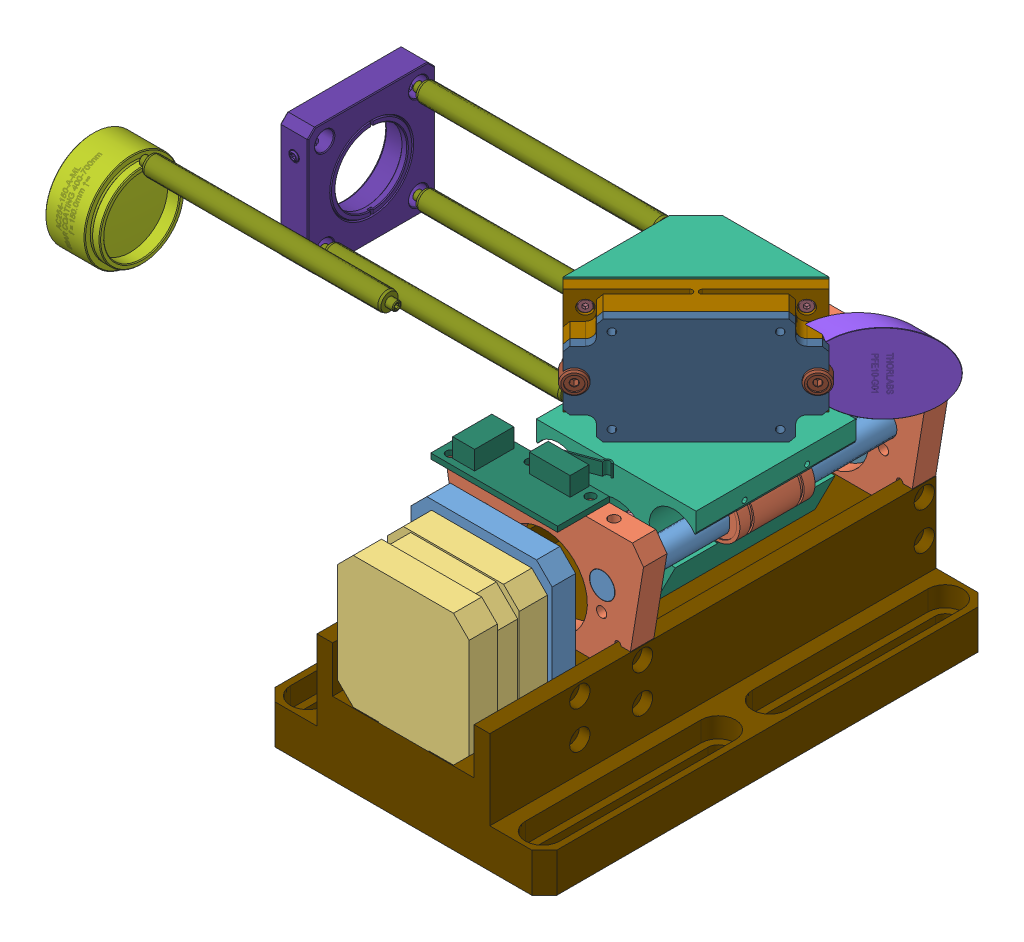
SolidWorks assembly Linear Stage, configuration Default. Lengths in mm.
Overall size (175.66 121.54 148).
36 component instances, 22 part files, 72 mates.
Components (placement in the parent):
- BI004-A - Linear Axis 8mm-3: BI004-A - Linear Axis 8mm [Default] at (44.95 27.15 -20.5) x (0 0 -1) z (-0.759211 0.650845 0) size (97.5 8 8)
- LM8UU - LinearBearing8mm-1: LM8UU - LinearBearing8mm [Default] at (44.95 28.65 -68.9607) x (0 0 -1) z (0.208321 -0.978061 0) size (24 15 15)
- BI004-A - Linear Axis 8mm-2: BI004-A - Linear Axis 8mm [Default] at (81.95 27.15 -20.5) x (0 0 -1) z (0.802037 -0.597275 0) size (97.5 8 8)
- LM8UU - LinearBearing8mm-2: LM8UU - LinearBearing8mm [Default] at (81.95 28.65 -68.9607) x (0 0 -1) z (0.231278 0.972888 0) size (24 15 15)
- BI002-A - NEMA17-L27-1: BI002-A - NEMA17-L27 [Default] at (63.45 19.65 12) x (0 0 1) z (-1 0 0) size (51 48 42)
- TR8x2 - TrapeziumStud8mm-1: TR8x2 - TrapeziumStud8mm [Default] at (63.45 19.65 -37.5) x (0 0 -1) z (-0.999958 0.009122 0) size (87.25 8 9.24)
- TR8x2 - LeadScrew8mm-1: TR8x2 - LeadScrew8mm [Default] at (63.45 19.65 -92.9607) x (0 0 -1) z (0.707107 -0.707107 0) size (15.5 22 22)
- BI005-A - AxisAdapterInt5mmInt8mm-1: BI005-A - AxisAdapterInt5mmInt8mm [Default] at (63.45 19.65 -19.5) x (0 0 -1) z (0.820702 -0.571356 0) (suppressed, hidden)
- CR050-A - Mounting-1: CR050-A - Mounting [Default] at (63.45 39.65 -43.4607) x (-1 0 0) z (0 0 -1) size (51 66.5 51)
- AC254-150-A-ML-1: AC254-150-A-ML [Default] at (-56.1614 71.7257 -4.5809) x (-1 0 0) z (0 0.913882 -0.405979) size (15.71 30.48 30.48)
- PFE10-G01 - EllipticalMirrorSM1-1: PFE10-G01 - EllipticalMirrorSM1 [Default] at (94.0995 57.15 -93.9534) x (0 1 0) z (-1 0 -0.000029) size (25.4 25.4 33.53)
- CR049-A - MirrorRotMount-1: CR049-A - MirrorRotMount [Default] at (63.45 57.15 -68.9607) x (-0.707107 0 0.707107) z (-0.707107 0 -0.707107) size (60 34 12.75)
- CR047-A - BackPlateMirror-1: CR047-A - BackPlateMirror [Default] at (68.223 57.15 -64.1878) x (0.707107 0 -0.707107) z (0.707107 0 0.707107) size (60 34 3)
- MAS15-1: MAS15 [Default] at (79.8758 56.2761 -93.0822) x (0.592527 -0.545732 -0.592527) z (-0.707107 0 -0.707107) size (7.11 7.11 23.88)
- MAS15-2: MAS15 [Default] at (39.3448 58.0539 -52.5512) x (-0.582343 0.567233 0.582343) z (-0.707107 0 -0.707107) size (7.11 7.11 23.88)
- CR048-A - HoldPlate-3: CR048-A - HoldPlate [Default] at (64.1571 57.15 -68.2536) x (-0.707107 0 0.707107) z (0 -1 0) size (50.25 1 25.75)
- socket head cap screw_din-2: socket head cap screw_din [DIN 912 M2 x 3 --- 3N] at (44.0753 69.15 -52.9801) x (-0.707107 0 -0.707107) z (0.707107 0 -0.707107) size (5 3.8 3.8)
- socket head cap screw_din-3: socket head cap screw_din [DIN 912 M2 x 3 --- 3N] at (44.0753 45.15 -52.9801) x (-0.707107 0 -0.707107) z (0.707107 0 -0.707107) size (5 3.8 3.8)
- socket head cap screw_din-4: socket head cap screw_din [DIN 912 M2 x 3 --- 3N] at (79.4306 69.15 -88.3355) x (-0.707107 0 -0.707107) z (0.707107 0 -0.707107) size (5 3.8 3.8)
- socket head cap screw_din-5: socket head cap screw_din [DIN 912 M2 x 3 --- 3N] at (79.4306 45.15 -88.3355) x (-0.707107 0 -0.707107) z (0.707107 0 -0.707107) size (5 3.8 3.8)
- KFL8 - RotationBearing8mm-1: KFL8 - RotationBearing8mm [Default] at (63.45 19.65 -122.5) x (-1 0 0) z (0 1 0) size (47.5 11 26.5)
- BI005-A - SwitchSensor-1: BI005-A - SwitchSensor [Default] at (36.1991 43.65 -11.5) size (40.5 7.7 21.9)
- ER3-5: ER3 [Default] at (2.3359 42.613 -52.5039) x (0 0.898414 0.439149) z (0 -0.439149 0.898414) size (5.99 81.28 5.99)
- CP02_M-1: CP02_M [Default] at (-44.5855 57.15 -68.9607) x (0 0 -1) z (1 0 0) size (41.4 40.64 8.89)
- ER3-7: ER3 [Default] at (-0.4744 93.1408 2.1008) x (0 0.898414 0.439149) z (0 -0.439149 0.898414) size (5.99 81.28 5.99)
- ER3-6: ER3 [Default] at (2.3359 70.7018 -84.5388) x (0 -0.90168 0.432405) z (0 -0.432405 -0.90168) size (5.99 81.28 5.99)
- ER3-4: ER3 [Default] at (2.3359 42.5932 -82.4978) x (0 0.892461 0.451125) z (0 -0.451125 0.892461) size (5.99 81.28 5.99)
- CR044-A - BasePlateStage-1: CR044-A - BasePlateStage [Default] at (63.45 -24.85 -46.75) x (0 0 -1) z (1 0 0) size (142.5 38 90)
- CR046-A - StepConnectPlate-1: CR046-A - StepConnectPlate [Default] at (63.45 21.15 -8) x (1 0 0) z (0 -1 0) size (45 7.5 50)
- CR045-A - MountingPlate-3: CR045-A - MountingPlate [Default] at (63.45 -1.35 -28) x (1 0 0) z (0 -1 0) size (63.48 7.5 50)
- CR045-A - MountingPlate-2: CR045-A - MountingPlate [Default] at (63.45 -1.35 -118) x (1 0 0) z (0 -1 0) size (63.48 7.5 50)
- socket head cap screw_din-8: socket head cap screw_din [DIN 912 M3 x 8 --- 8N] at (69.1069 25.3069 -95.9607) x (0 0 1) z (-1 0 0) size (11 5.5 5.5)
- socket head cap screw_din-9: socket head cap screw_din [DIN 912 M3 x 8 --- 8N] at (57.7931 25.3069 -95.9607) x (0 0 1) z (-1 0 0) size (11 5.5 5.5)
- socket head cap screw_din-10: socket head cap screw_din [DIN 912 M3 x 8 --- 8N] at (57.7931 13.9931 -95.9607) x (0 0 1) z (-1 0 0) size (11 5.5 5.5)
- socket head cap screw_din-11: socket head cap screw_din [DIN 912 M3 x 8 --- 8N] at (69.1069 13.9931 -95.9607) x (0 0 1) z (-1 0 0) size (11 5.5 5.5)
- TR8x2 - FollowScrew8mm-1: TR8x2 - FollowScrew8mm [Default] at (63.45 19.65 -61.9607) x (0 0 1) z (-0.742227 -0.670149 0) size (15.5 14 14)
Mates (geometry in assembly coordinates):
- Coincident2: coincident: plane of BI002-A - NEMA17-L27-1 through (63.45 19.65 24.5) normal (0 0 1); plane of CR044-A - BasePlateStage-1 through (63.45 -12.35 24.5) normal (0 0 1)
- Concentric1: concentric: cylinder of BI002-A - NEMA17-L27-1 through (63.45 19.65 -26.5) axis (0 0 1) radius 2.5; cylinder of BI005-A - AxisAdapterInt5mmInt8mm-1 through (63.45 19.65 -26.5) axis (0 0 1) radius 2.5
- Coincident3: coincident: plane of BI002-A - NEMA17-L27-1 through (63.45 19.65 -26.5) normal (0 0 -1); plane of BI005-A - AxisAdapterInt5mmInt8mm-1 through (63.45 19.65 -26.5) normal (0 0 -1)
- Coincident4: coincident: plane of BI002-A - NEMA17-L27-1 through (63.45 19.65 -0.5) normal (0 0 -1); plane of CR046-A - StepConnectPlate-1 through (63.45 21.15 -0.5) normal (0 0 1)
- Concentric4: concentric: cylinder of BI002-A - NEMA17-L27-1 through (78.95 35.15 -0.5) axis (0 0 -1) radius 1.25; cylinder of CR046-A - StepConnectPlate-1 through (78.95 35.15 -8) axis (0 0 -1) radius 1.6
- Concentric5: concentric: cylinder of BI002-A - NEMA17-L27-1 through (47.95 4.15 -0.5) axis (0 0 -1) radius 1.25; cylinder of CR046-A - StepConnectPlate-1 through (47.95 4.15 -8) axis (0 0 -1) radius 1.6
- Concentric6: concentric: cylinder of TR8x2 - TrapeziumStud8mm-1 through (63.45 19.65 -42.5) axis (0 0 1) radius 1; cylinder of BI005-A - AxisAdapterInt5mmInt8mm-1 through (63.45 19.65 -26.5) axis (0 0 -1) radius 4
- Distance7: distance = 7 mm: plane of TR8x2 - TrapeziumStud8mm-1 through (63.45 19.65 -37.5) normal (0 0 1); plane of BI005-A - AxisAdapterInt5mmInt8mm-1 through (63.45 19.65 -44.5) normal (0 0 -1)
- Concentric7: concentric: cylinder of BI005-A - AxisAdapterInt5mmInt8mm-1 through (63.45 19.65 -44.5) axis (0 0 1) radius 9.5; cylinder of CR050-A - Mounting-1 through (63.45 19.65 -43.4597) axis (0 0 -1) radius 5.5
- Parallel1: parallel: plane of CR050-A - Mounting-1 through (88.95 39.65 -94.4607) normal (0 1 0); plane of CR044-A - BasePlateStage-1 through (63.45 13.15 -46.75) normal (0 1 0)
- Distance8: distance = 82 mm: cylinder of CR050-A - Mounting-1 through (88.951 57.15 -68.9607) axis (-1 0 0) radius 12.8397; plane of CR044-A - BasePlateStage-1 through (63.45 -24.85 -46.75) normal (0 -1 0)
- Width13: width: plane of BI002-A - NEMA17-L27-1 through (84.45 35.65 24.5) normal (1 0 0); plane of BI002-A - NEMA17-L27-1 through (42.45 3.65 24.5) normal (-1 0 0); plane of CR044-A - BasePlateStage-1 through (40.85 5.15 24.5) normal (1 0 0); plane of CR044-A - BasePlateStage-1 through (86.05 5.15 24.5) normal (-1 0 0)
- Width14: width: plane of CR045-A - MountingPlate-3 through (40.95 13.25 -20.5) normal (-1 0 0); plane of CR045-A - MountingPlate-3 through (85.95 -1.35 -20.5) normal (1 0 0); plane of CR044-A - BasePlateStage-1 through (40.85 5.15 24.5) normal (1 0 0); plane of CR044-A - BasePlateStage-1 through (86.05 5.15 24.5) normal (-1 0 0)
- Width16: width: plane of CR045-A - MountingPlate-2 through (85.95 -1.35 -110.5) normal (1 0 0); plane of CR045-A - MountingPlate-2 through (40.95 13.25 -110.5) normal (-1 0 0); plane of CR044-A - BasePlateStage-1 through (86.05 5.15 24.5) normal (-1 0 0); plane of CR044-A - BasePlateStage-1 through (40.85 5.15 24.5) normal (1 0 0)
- Coincident9: coincident: plane of CR044-A - BasePlateStage-1 through (63.45 -12.35 -118) normal (0 0 -1); plane of CR045-A - MountingPlate-2 through (63.45 -1.35 -118) normal (0 0 -1)
- Concentric8: concentric: cylinder of KFL8 - RotationBearing8mm-1 through (63.45 19.65 -118) axis (0 0 -1) radius 13.25; cylinder of CR045-A - MountingPlate-2 through (63.45 19.65 -118.001) axis (0 0 1) radius 13.75
- Coincident11: coincident: plane of KFL8 - RotationBearing8mm-1 through (63.45 19.65 -118) normal (0 0 1); plane of CR045-A - MountingPlate-2 through (63.45 -1.35 -118) normal (0 0 -1)
- Concentric9: concentric: cylinder of KFL8 - RotationBearing8mm-1 through (81.75 19.65 -118) axis (0 0 -1) radius 2.65; cylinder of CR045-A - MountingPlate-2 through (81.75 19.65 -118) axis (0 0 -1) radius 1.65
- Width17: width: plane of CR044-A - BasePlateStage-1 through (86.05 -6.35 -28.1) normal (0 0 1); plane of CR044-A - BasePlateStage-1 through (86.05 -6.35 -20.4) normal (0 0 -1); plane of CR045-A - MountingPlate-3 through (63.45 -1.35 -20.5) normal (0 0 1); plane of CR045-A - MountingPlate-3 through (63.45 -1.35 -28) normal (0 0 -1)
- Concentric10: concentric: cylinder of BI004-A - Linear Axis 8mm-2 through (81.95 27.15 -118) axis (0 0 1) radius 4; cylinder of CR045-A - MountingPlate-3 through (81.95 27.15 -20.499) axis (0 0 -1) radius 4.1
- Concentric11: concentric: cylinder of BI004-A - Linear Axis 8mm-3 through (44.95 27.15 -118) axis (0 0 1) radius 4; cylinder of CR045-A - MountingPlate-3 through (44.95 27.15 -20.499) axis (0 0 -1) radius 4.1
- Concentric12: concentric: cylinder of LM8UU - LinearBearing8mm-2 through (81.95 28.65 -58.2941) axis (0 0 1) radius 7.5; cylinder of CR050-A - Mounting-1 through (81.95 28.65 -43.4597) axis (0 0 -1) radius 7.75
- Width18: width: plane of CR050-A - Mounting-1 through (63.45 39.65 -94.4607) normal (0 0 -1); plane of CR050-A - Mounting-1 through (63.45 39.65 -43.4607) normal (0 0 1); plane of LM8UU - LinearBearing8mm-2 through (80.4467 22.3262 -57.2107) normal (0 0 1); plane of LM8UU - LinearBearing8mm-2 through (81.0249 24.7584 -80.7107) normal (0 0 -1)
- Concentric13: concentric: cylinder of LM8UU - LinearBearing8mm-1 through (44.95 28.65 -58.2941) axis (0 0 1) radius 7.5; cylinder of CR050-A - Mounting-1 through (44.95 28.65 -43.4597) axis (0 0 -1) radius 7.75
- Width19: width: plane of CR050-A - Mounting-1 through (63.45 39.65 -43.4607) normal (0 0 1); plane of CR050-A - Mounting-1 through (63.45 39.65 -94.4607) normal (0 0 -1); plane of LM8UU - LinearBearing8mm-1 through (43.5959 35.0074 -57.2107) normal (0 0 1); plane of LM8UU - LinearBearing8mm-1 through (44.1167 32.5622 -80.7107) normal (0 0 -1)
- Width20: width: plane of CR045-A - MountingPlate-3 through (63.45 -1.35 -20.5) normal (0 0 1); plane of CR045-A - MountingPlate-2 through (63.45 -1.35 -118) normal (0 0 -1); plane of BI004-A - Linear Axis 8mm-2 through (81.95 27.15 -118) normal (0 0 -1); plane of BI004-A - Linear Axis 8mm-2 through (81.95 27.15 -20.5) normal (0 0 1)
- Coincident14: coincident: plane of BI004-A - Linear Axis 8mm-3 through (44.95 27.15 -20.5) normal (0 0 1); plane of BI004-A - Linear Axis 8mm-2 through (81.95 27.15 -20.5) normal (0 0 1)
- Coincident15: coincident: plane of CR044-A - BasePlateStage-1 through (63.45 -6.35 -46.75) normal (0 1 0); plane of CR045-A - MountingPlate-3 through (63.45 -6.35 -28) normal (0 -1 0)
- Coincident16: coincident: plane of CR044-A - BasePlateStage-1 through (63.45 -6.35 -46.75) normal (0 1 0); plane of CR045-A - MountingPlate-2 through (63.45 -6.35 -118) normal (0 -1 0)
- LimitDistance1: limit distance = 15.4607 mm: plane of CR050-A - Mounting-1 through (63.45 39.65 -43.4607) normal (0 0 1); plane of CR045-A - MountingPlate-3 through (63.45 -1.35 -28) normal (0 0 -1)
- Concentric14: concentric: cylinder of CR050-A - Mounting-1 through (76.885 69.15 -90.8811) axis (0.707107 0 0.707107) radius 0.8; cylinder of CR049-A - MirrorRotMount-1 through (79.7135 69.15 -88.0526) axis (0.707107 0 0.707107) radius 2.2
- Concentric15: concentric: cylinder of CR050-A - Mounting-1 through (41.5297 45.15 -55.5257) axis (0.707107 0 0.707107) radius 0.8; cylinder of CR049-A - MirrorRotMount-1 through (44.3581 45.15 -52.6973) axis (0.707107 0 0.707107) radius 2.2
- Coincident17: coincident: plane of CR050-A - Mounting-1 through (37.9942 74.65 -51.9902) normal (0.707107 0 0.707107); plane of CR049-A - MirrorRotMount-1 through (85.7239 74.15 -99.7199) normal (-0.707107 0 -0.707107)
- Concentric18: concentric: cylinder of CR049-A - MirrorRotMount-1 through (78.2992 49.65 -82.3958) axis (-0.707107 0 -0.707107) radius 0.8; cylinder of CR048-A - HoldPlate-3 through (77.5921 49.65 -83.1029) axis (-0.707107 0 -0.707107) radius 1.1
- Concentric19: concentric: cylinder of CR049-A - MirrorRotMount-1 through (50.015 64.65 -54.1115) axis (-0.707107 0 -0.707107) radius 0.8; cylinder of CR048-A - HoldPlate-3 through (49.3079 64.65 -54.8186) axis (-0.707107 0 -0.707107) radius 1.1
- Coincident18: coincident: plane of CR049-A - MirrorRotMount-1 through (72.9145 57.15 -77.011) normal (-0.707107 0 -0.707107); plane of CR048-A - HoldPlate-3 through (72.8192 57.15 -76.9157) normal (0.707107 0 0.707107)
- Concentric20: concentric: cylinder of CR049-A - MirrorRotMount-1 through (54.7879 70.65 -50.7527) axis (0.707107 0 0.707107) radius 0.8; cylinder of CR047-A - BackPlateMirror-1 through (56.9093 70.65 -48.6314) axis (0.707107 0 0.707107) radius 1.1
- Concentric21: concentric: cylinder of CR049-A - MirrorRotMount-1 through (81.658 43.65 -77.6228) axis (0.707107 0 0.707107) radius 0.8; cylinder of CR047-A - BackPlateMirror-1 through (83.7793 43.65 -75.5015) axis (0.707107 0 0.707107) radius 1.1
- Coincident19: coincident: plane of CR049-A - MirrorRotMount-1 through (68.223 57.15 -64.1878) normal (0.707107 0 0.707107); plane of CR047-A - BackPlateMirror-1 through (68.223 57.15 -64.1878) normal (-0.707107 0 -0.707107)
- Coincident20: coincident: plane of PFE10-G01 - EllipticalMirrorSM1-1 through (102.5566 32.15 -106.6531) normal (-0.707107 0 -0.707107); plane of CR048-A - HoldPlate-3 through (72.8192 57.15 -76.9157) normal (0.707107 0 0.707107)
- Width22: width: plane of CR049-A - MirrorRotMount-1 through (63.45 74.15 -68.9607) normal (0 1 0); plane of CR049-A - MirrorRotMount-1 through (63.45 40.15 -68.9607) normal (0 -1 0); cylinder of PFE10-G01 - EllipticalMirrorSM1-1 through (69.0995 57.15 -93.9541) axis (1 0 0.000029) radius 12.7
- Concentric23: concentric: cylinder of CR050-A - Mounting-1 through (88.951 57.15 -68.9607) axis (-1 0 0) radius 12.8397; cylinder of CP02_M-1 through (-49.0305 57.15 -68.9607) axis (1 0 0) radius 13.1445
- Parallel2: parallel: plane of CR050-A - Mounting-1 through (63.45 74.65 -43.4607) normal (0 1 0); plane of CP02_M-1 through (-40.1405 77.47 -68.9607) normal (0 1 0)
- Coincident21: coincident: plane of BI005-A - SwitchSensor-1 through (36.1991 43.65 -11.5) normal (0 -1 0); plane of CR045-A - MountingPlate-3 through (95.95 43.65 -20.5) normal (0 1 0)
- Coincident22: coincident: plane of BI005-A - SwitchSensor-1 through (36.1991 45.35 -28) normal (0 0 -1); plane of CR045-A - MountingPlate-3 through (63.45 -1.35 -28) normal (0 0 -1)
- Tangent2: tangent: cylinder of PFE10-G01 - EllipticalMirrorSM1-1 through (69.0995 57.15 -93.9541) axis (1 0 0.000029) radius 12.7; curve of CR049-A - MirrorRotMount-1
- Coincident23: coincident: plane of CR049-A - MirrorRotMount-1 through (77.1679 45.15 -88.9012) normal (0.707107 0 0.707107); plane of socket head cap screw_din-5 through (78.0164 47.05 -89.7497) normal (-0.707107 0 -0.707107)
- Concentric24: concentric: cylinder of CR049-A - MirrorRotMount-1 through (79.7135 45.15 -88.0526) axis (0.707107 0 0.707107) radius 1.2; cylinder of socket head cap screw_din-5 through (101.8813 45.15 -65.8848) axis (0.707107 0 0.707107) radius 1
- Coincident24: coincident: plane of CR049-A - MirrorRotMount-1 through (77.1679 69.15 -88.9012) normal (0.707107 0 0.707107); plane of socket head cap screw_din-4 through (78.0164 71.05 -89.7497) normal (-0.707107 0 -0.707107)
- Concentric25: concentric: cylinder of CR049-A - MirrorRotMount-1 through (79.7135 69.15 -88.0526) axis (0.707107 0 0.707107) radius 1.2; cylinder of socket head cap screw_din-4 through (101.8813 69.15 -65.8848) axis (0.707107 0 0.707107) radius 1
- Coincident25: coincident: plane of CR049-A - MirrorRotMount-1 through (41.8125 69.15 -53.5458) normal (0.707107 0 0.707107); plane of socket head cap screw_din-2 through (42.6611 71.05 -54.3943) normal (-0.707107 0 -0.707107)
- Concentric26: concentric: cylinder of CR049-A - MirrorRotMount-1 through (44.3581 69.15 -52.6973) axis (0.707107 0 0.707107) radius 1.2; cylinder of socket head cap screw_din-2 through (66.5259 69.15 -30.5295) axis (0.707107 0 0.707107) radius 1
- Concentric27: concentric: cylinder of CR049-A - MirrorRotMount-1 through (44.3581 45.15 -52.6973) axis (0.707107 0 0.707107) radius 1.2; cylinder of socket head cap screw_din-3 through (66.5259 45.15 -30.5295) axis (0.707107 0 0.707107) radius 1
- Coincident26: coincident: plane of CR049-A - MirrorRotMount-1 through (41.8125 45.15 -53.5458) normal (0.707107 0 0.707107); plane of socket head cap screw_din-3 through (42.6611 47.05 -54.3943) normal (-0.707107 0 -0.707107)
- Concentric28: concentric: cylinder of CR047-A - BackPlateMirror-1 through (50.8989 57.15 -42.621) axis (0.707107 0 0.707107) radius 1.6; cylinder of MAS15-2 through (34.9063 57.15 -58.6135) axis (-0.707107 0 -0.707107) radius 1.5
- Concentric29: concentric: cylinder of CR047-A - BackPlateMirror-1 through (89.7897 57.15 -81.5119) axis (0.707107 0 0.707107) radius 1.6; cylinder of MAS15-1 through (73.7972 57.15 -97.5044) axis (-0.707107 0 -0.707107) radius 1.5
- Coincident28: coincident: plane of MAS15-1 through (86.9172 60.3212 -77.4982) normal (0.707107 0 0.707107); plane of MAS15-2 through (54.8533 53.8539 -45.4344) normal (0.707107 0 0.707107)
- Concentric30: concentric: cylinder of TR8x2 - LeadScrew8mm-1 through (69.1069 25.3069 -77.4597) axis (0 0 -1) radius 1.75; cylinder of CR050-A - Mounting-1 through (69.1069 25.3069 -94.4607) axis (0 0 -1) radius 1.25
- Concentric31: concentric: cylinder of TR8x2 - LeadScrew8mm-1 through (57.7931 25.3069 -77.4597) axis (0 0 -1) radius 1.75; cylinder of CR050-A - Mounting-1 through (57.7931 25.3069 -94.4607) axis (0 0 -1) radius 1.25
- Coincident30: coincident: plane of TR8x2 - LeadScrew8mm-1 through (59.7377 23.3623 -88.9607) normal (0 0 1); plane of CR050-A - Mounting-1 through (63.45 19.65 -88.9607) normal (0 0 -1)
- Concentric32: concentric: cylinder of TR8x2 - LeadScrew8mm-1 through (69.1069 25.3069 -77.4597) axis (0 0 -1) radius 1.75; cylinder of socket head cap screw_din-8 through (69.1069 25.3069 -127.7107) axis (0 0 -1) radius 2.75
- Coincident31: coincident: plane of TR8x2 - LeadScrew8mm-1 through (55.6718 27.4282 -92.9607) normal (0 0 -1); plane of socket head cap screw_din-8 through (69.1069 28.0569 -92.9607) normal (0 0 1)
- Concentric33: concentric: cylinder of TR8x2 - LeadScrew8mm-1 through (57.7931 25.3069 -77.4597) axis (0 0 -1) radius 1.75; cylinder of socket head cap screw_din-9 through (57.7931 25.3069 -127.7107) axis (0 0 -1) radius 2.75
- Coincident32: coincident: plane of TR8x2 - LeadScrew8mm-1 through (55.6718 27.4282 -92.9607) normal (0 0 -1); plane of socket head cap screw_din-9 through (57.7931 28.0569 -92.9607) normal (0 0 1)
- Concentric34: concentric: cylinder of TR8x2 - LeadScrew8mm-1 through (57.7931 13.9931 -77.4597) axis (0 0 -1) radius 1.75; cylinder of socket head cap screw_din-10 through (57.7931 13.9931 -127.7107) axis (0 0 -1) radius 2.75
- Coincident33: coincident: plane of TR8x2 - LeadScrew8mm-1 through (55.6718 27.4282 -92.9607) normal (0 0 -1); plane of socket head cap screw_din-10 through (57.7931 16.7431 -92.9607) normal (0 0 1)
- Concentric35: concentric: cylinder of TR8x2 - LeadScrew8mm-1 through (69.1069 13.9931 -77.4597) axis (0 0 -1) radius 1.75; cylinder of socket head cap screw_din-11 through (69.1069 13.9931 -127.7107) axis (0 0 -1) radius 2.75
- Coincident34: coincident: plane of TR8x2 - LeadScrew8mm-1 through (55.6718 27.4282 -92.9607) normal (0 0 -1); plane of socket head cap screw_din-11 through (69.1069 16.7431 -92.9607) normal (0 0 1)
- Concentric36: concentric: cylinder of TR8x2 - LeadScrew8mm-1 through (63.45 19.65 -49.2534) axis (0 0 1) radius 5.25; cylinder of TR8x2 - FollowScrew8mm-1 through (63.45 19.65 -67.0954) axis (0 0 -1) radius 5.25
- Parallel3: parallel: line of TR8x2 - LeadScrew8mm-1 through (61.4318 24.4966 -81.4607) axis (0 0 1); line of TR8x2 - FollowScrew8mm-1 through (61.4318 24.4966 -73.4607) axis (0 0 -1)
- Coincident35: coincident: line of TR8x2 - LeadScrew8mm-1 through (61.4318 24.4966 -81.4607) axis (0 0 1); line of TR8x2 - FollowScrew8mm-1 through (61.4318 24.4966 -73.4607) axis (0 0 -1)
- Coincident36: coincident: plane of TR8x2 - LeadScrew8mm-1 through (60.6216 22.4784 -77.4607) normal (0 0 1); plane of TR8x2 - FollowScrew8mm-1 through (67.3467 23.1683 -77.4607) normal (0 0 -1)
